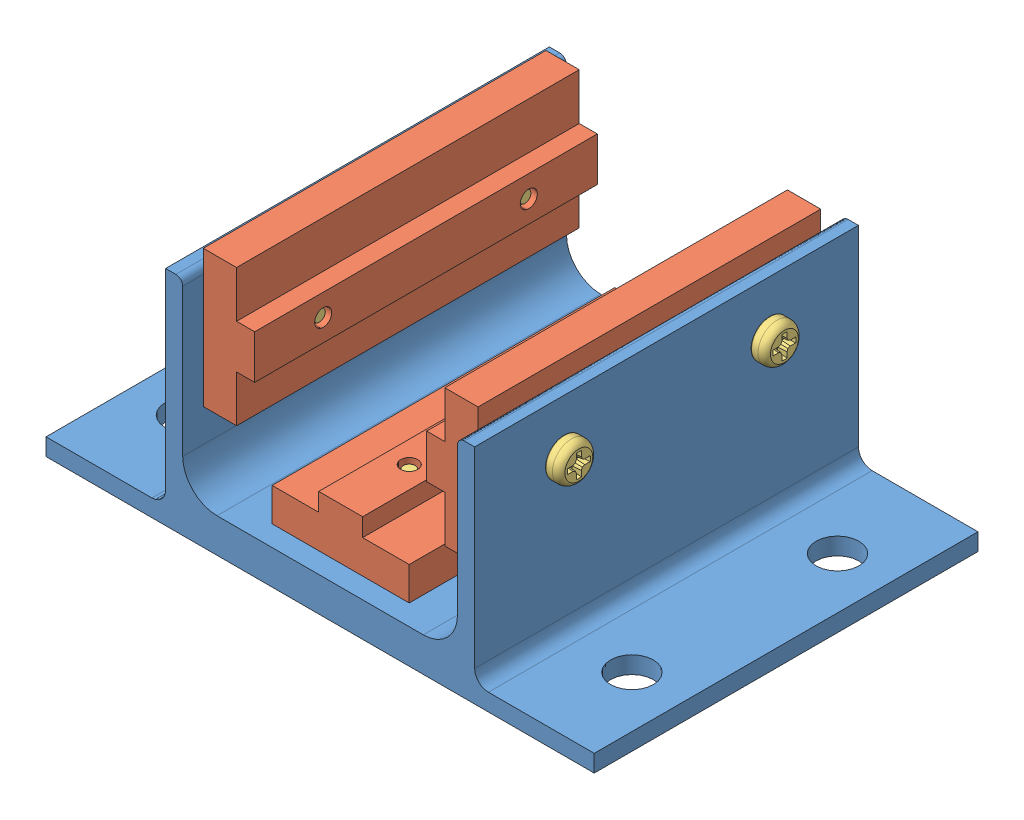
SolidWorks assembly Carrige Sled Assem, configuration Default. Lengths in mm.
Overall size (101.6 44.2 71.12).
10 component instances, 3 part files, 27 mates.
Components (placement in the parent):
- Carrige sled-1: Carrige sled [9017K481] at (109.0051 167.0863 231.0243) size (101.6 41.27 71.12)
- Plastic sled-1: Plastic sled [Default] at (121.7686 167.0863 234.8343) x (1 0 0) z (0 -1 0) size (25.4 63.5 9.53)
- Plastic sled-2: Plastic sled [Default] at (109.0051 179.5323 298.3343) x (0 1 0) z (-1 0 0) size (25.4 63.5 9.53)
- 99461A966_Phillips Rounded Head Thread-Forming Screws-1: 99461A966_Phillips Rounded Head Thread-Forming Screws [99461A966] at (105.8301 192.2323 285.6343) x (0 1 0) z (-1 0 0) size (7 7 14.96)
- 99461A966_Phillips Rounded Head Thread-Forming Screws-2: 99461A966_Phillips Rounded Head Thread-Forming Screws [99461A966] at (134.4686 163.9113 285.6343) x (-1 0 0) z (0 -1 0) size (7 7 14.96)
- 99461A966_Phillips Rounded Head Thread-Forming Screws-3: 99461A966_Phillips Rounded Head Thread-Forming Screws [99461A966] at (105.8301 192.2323 247.5343) x (0 0 1) z (-1 0 0) size (7 7 14.96)
- 99461A966_Phillips Rounded Head Thread-Forming Screws-4: 99461A966_Phillips Rounded Head Thread-Forming Screws [99461A966] at (134.4686 163.9113 247.5343) x (-1 0 0) z (0 -1 0) size (7 7 14.96)
- 99461A966_Phillips Rounded Head Thread-Forming Screws-5: 99461A966_Phillips Rounded Head Thread-Forming Screws [99461A966] at (163.1071 192.2323 247.5343) x (0 -1 0) z (1 0 0) size (7 7 14.96)
- 99461A966_Phillips Rounded Head Thread-Forming Screws-6: 99461A966_Phillips Rounded Head Thread-Forming Screws [99461A966] at (163.1071 192.2323 285.6343) x (0 -1 0) z (1 0 0) size (7 7 14.96)
- Plastic sled-3: Plastic sled [Default] at (159.9321 204.9323 298.3343) x (0 -1 0) z (1 0 0) size (25.4 63.5 9.53)
Mates (geometry in assembly coordinates):
- Concentric2: concentric aligned: cylinder of Carrige sled-1 through (134.4686 202.0113 285.6343) axis (0 -1 0) radius 2.0193; cylinder of Plastic sled-1 through (134.4686 230.5863 285.6343) axis (0 -1 0) radius 1.5875
- Coincident2: coincident anti-aligned: plane of Carrige sled-1 through (142.6601 167.0863 302.1443) normal (0 1 0); plane of Plastic sled-1 through (121.7686 167.0863 298.3343) normal (0 -1 0)
- Concentric3: concentric aligned: cylinder of Carrige sled-1 through (134.4686 202.0113 247.5343) axis (0 -1 0) radius 2.0193; cylinder of Plastic sled-1 through (134.4686 230.5863 247.5343) axis (0 -1 0) radius 1.5875
- Concentric4: concentric aligned: cylinder of Carrige sled-1 through (185.2686 192.2323 247.5343) axis (-1 0 0) radius 2.0193; cylinder of Plastic sled-2 through (172.5051 192.2323 247.5343) axis (-1 0 0) radius 1.5875
- Concentric5: concentric aligned: cylinder of Carrige sled-1 through (185.2686 192.2323 285.6343) axis (-1 0 0) radius 2.0193; cylinder of Plastic sled-2 through (172.5051 192.2323 285.6343) axis (-1 0 0) radius 1.5875
- Coincident3: coincident anti-aligned: plane of Carrige sled-1 through (109.0051 173.4363 302.1443) normal (1 0 0); plane of Plastic sled-2 through (109.0051 179.5323 234.8343) normal (-1 0 0)
- Concentric7: concentric aligned: cylinder of Carrige sled-1 through (185.2686 192.2323 285.6343) axis (-1 0 0) radius 2.0193; circle of 99461A966_Phillips Rounded Head Thread-Forming Screws-1
- Coincident5: coincident anti-aligned: plane of Carrige sled-1 through (105.8301 163.9113 302.1443) normal (-1 0 0); plane of 99461A966_Phillips Rounded Head Thread-Forming Screws-1 through (105.8301 192.2323 284.5493) normal (1 0 0)
- Concentric8: concentric aligned: cylinder of Carrige sled-1 through (134.4686 202.0113 285.6343) axis (0 -1 0) radius 2.0193; cylinder of 99461A966_Phillips Rounded Head Thread-Forming Screws-2 through (134.4686 164.5113 285.6343) axis (0 -1 0) radius 2
- Coincident6: coincident anti-aligned: plane of Carrige sled-1 through (134.4686 163.9113 285.6343) normal (0 -1 0); plane of 99461A966_Phillips Rounded Head Thread-Forming Screws-2 through (134.4686 163.9113 284.5493) normal (0 1 0)
- Concentric9: concentric anti-aligned: cylinder of Carrige sled-1 through (185.2686 192.2323 247.5343) axis (-1 0 0) radius 2.0193; cylinder of Plastic sled-3 through (96.4321 192.2323 247.5343) axis (1 0 0) radius 1.5875
- Coincident7: coincident anti-aligned: plane of Carrige sled-1 through (159.9321 202.0113 302.1443) normal (-1 0 0); plane of Plastic sled-3 through (159.9321 204.9323 234.8343) normal (1 0 0)
- Concentric10: concentric anti-aligned: cylinder of Carrige sled-1 through (185.2686 192.2323 285.6343) axis (-1 0 0) radius 2.0193; cylinder of Plastic sled-3 through (96.4321 192.2323 285.6343) axis (1 0 0) radius 1.5875
- Concentric11: concentric anti-aligned: cylinder of Carrige sled-1 through (185.2686 192.2323 247.5343) axis (-1 0 0) radius 2.0193; cylinder of 99461A966_Phillips Rounded Head Thread-Forming Screws-5 through (162.5071 192.2323 247.5343) axis (1 0 0) radius 2
- Coincident8: coincident anti-aligned: plane of Carrige sled-1 through (163.1071 163.9113 302.1443) normal (1 0 0); plane of 99461A966_Phillips Rounded Head Thread-Forming Screws-5 through (163.1071 192.2323 246.4493) normal (-1 0 0)
- Concentric12: concentric anti-aligned: cylinder of Carrige sled-1 through (185.2686 192.2323 285.6343) axis (-1 0 0) radius 2.0193; cylinder of 99461A966_Phillips Rounded Head Thread-Forming Screws-6 through (162.5071 192.2323 285.6343) axis (1 0 0) radius 2
- Coincident9: coincident anti-aligned: plane of Carrige sled-1 through (163.1071 163.9113 302.1443) normal (1 0 0); plane of 99461A966_Phillips Rounded Head Thread-Forming Screws-6 through (163.1071 192.2323 284.5493) normal (-1 0 0)
- Concentric13: concentric aligned: cylinder of Carrige sled-1 through (185.2686 192.2323 247.5343) axis (-1 0 0) radius 2.0193; cylinder of 99461A966_Phillips Rounded Head Thread-Forming Screws-3 through (106.4301 192.2323 247.5343) axis (-1 0 0) radius 2
- Coincident10: coincident anti-aligned: plane of Carrige sled-1 through (105.8301 163.9113 302.1443) normal (-1 0 0); plane of 99461A966_Phillips Rounded Head Thread-Forming Screws-3 through (105.8301 193.3173 247.5343) normal (1 0 0)
- Concentric14: concentric aligned: cylinder of Carrige sled-1 through (134.4686 202.0113 247.5343) axis (0 -1 0) radius 2.0193; cylinder of 99461A966_Phillips Rounded Head Thread-Forming Screws-4 through (134.4686 164.5113 247.5343) axis (0 -1 0) radius 2
- Coincident11: coincident anti-aligned: plane of Carrige sled-1 through (134.4686 163.9113 247.5343) normal (0 -1 0); plane of 99461A966_Phillips Rounded Head Thread-Forming Screws-4 through (134.4686 163.9113 246.4493) normal (0 1 0)
- Parallel1: parallel anti-aligned: plane of Carrige sled-1 through (109.0051 167.0863 231.0243) normal (0 0 1); plane of 99461A966_Phillips Rounded Head Thread-Forming Screws-1 through (105.8301 192.2323 285.6343) normal (0 0 -1)
- Parallel2: parallel anti-aligned: plane of Carrige sled-1 through (109.0051 167.0863 231.0243) normal (0 0 1); plane of 99461A966_Phillips Rounded Head Thread-Forming Screws-2 through (134.4686 163.9113 285.6343) normal (0 0 -1)
- Parallel3: parallel aligned: plane of Carrige sled-1 through (109.0051 167.0863 231.0243) normal (0 0 1); plane of 99461A966_Phillips Rounded Head Thread-Forming Screws-3 through (105.8301 192.2323 247.5343) normal (0 0 1)
- Parallel4: parallel anti-aligned: plane of Carrige sled-1 through (109.0051 167.0863 231.0243) normal (0 0 1); plane of 99461A966_Phillips Rounded Head Thread-Forming Screws-4 through (134.4686 163.9113 247.5343) normal (0 0 -1)
- Parallel5: parallel anti-aligned: plane of Carrige sled-1 through (109.0051 167.0863 231.0243) normal (0 0 1); plane of 99461A966_Phillips Rounded Head Thread-Forming Screws-5 through (163.1071 192.2323 247.5343) normal (0 0 -1)
- Parallel6: parallel anti-aligned: plane of Carrige sled-1 through (109.0051 167.0863 231.0243) normal (0 0 1); plane of 99461A966_Phillips Rounded Head Thread-Forming Screws-6 through (163.1071 192.2323 285.6343) normal (0 0 -1)
